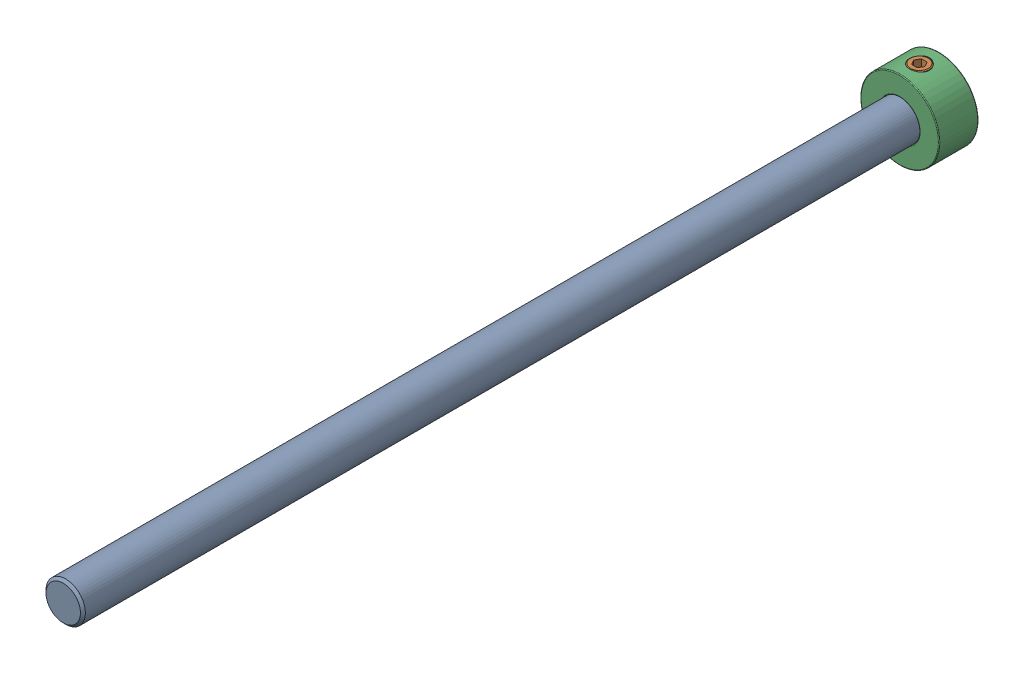
SolidWorks assembly SSDCT Guide Rod Asmbly_1, configuration Default. Lengths in mm.
Overall size (16 16 180).
2 component instances, 2 part files, 0 mates.
Components (placement in the parent):
- SSDCT 8mm x 180mm Rod-1: SSDCT 8mm x 180mm Rod [Default] at origin size (8 8 180)
- 57485K67-1: 57485K67 [57485K67] at (-26 0 18) size (16 16 8)
